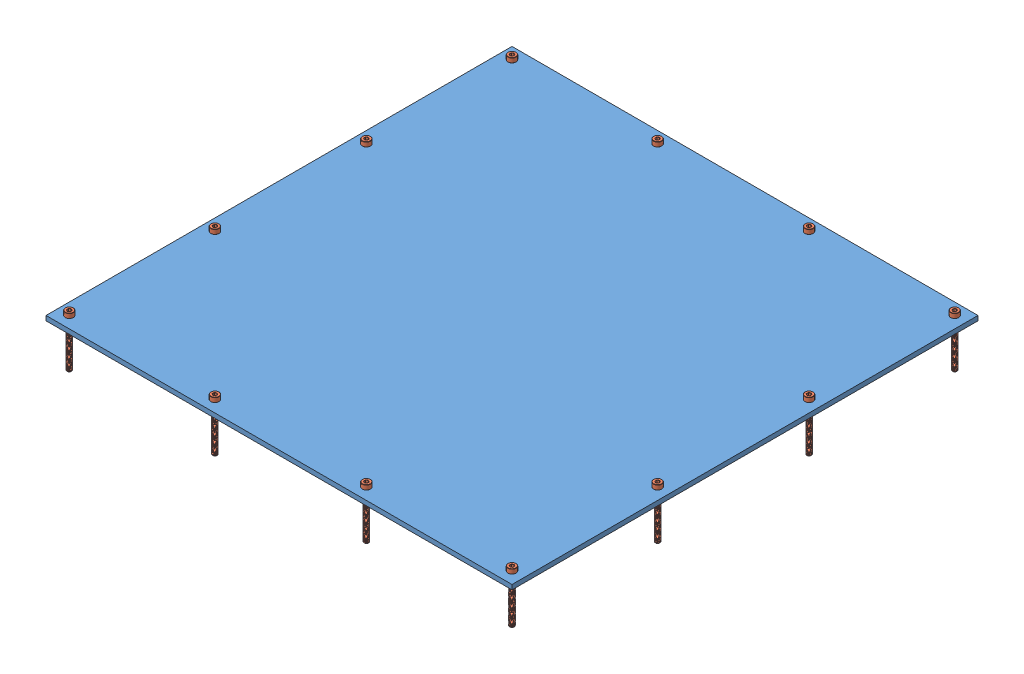
SolidWorks assembly Assem1, configuration Default. Lengths in mm.
Overall size (400 45 400).
13 component instances, 2 part files, 2 mates.
Components (placement in the parent):
- AluminumPlate-1: AluminumPlate [Default] at (130.93 169.5501 342.0003) size (400 4 400)
- M4_41MM-1: M4_41MM [По умолчанию] at (-59.07 173.5501 532.0003) x (0.999999 0 0.001128) z (-0.001128 0 0.999999) size (7 45 7)
- M4_41MM-2: M4_41MM [По умолчанию] at (-59.07 173.5501 407.0003) x (0.999999 0 0.001128) z (-0.001128 0 0.999999) size (7 45 7)
- M4_41MM-3: M4_41MM [По умолчанию] at (65.93 173.5501 532.0003) x (0.999999 0 0.001128) z (-0.001128 0 0.999999) size (7 45 7)
- M4_41MM-5: M4_41MM [По умолчанию] at (-59.07 173.5501 277.0003) x (0.999999 0 -0.001128) z (0.001128 0 0.999999) size (7 45 7)
- M4_41MM-6: M4_41MM [По умолчанию] at (-59.07 173.5501 152.0003) x (0.999999 0 -0.001128) z (0.001128 0 0.999999) size (7 45 7)
- M4_41MM-7: M4_41MM [По умолчанию] at (65.93 173.5501 152.0003) x (0.999999 0 -0.001128) z (0.001128 0 0.999999) size (7 45 7)
- M4_41MM-8: M4_41MM [По умолчанию] at (195.93 173.5501 152.0003) x (-0.999999 0 -0.001128) z (0.001128 0 -0.999999) size (7 45 7)
- M4_41MM-9: M4_41MM [По умолчанию] at (320.93 173.5501 152.0003) x (-0.999999 0 -0.001128) z (0.001128 0 -0.999999) size (7 45 7)
- M4_41MM-10: M4_41MM [По умолчанию] at (320.93 173.5501 277.0003) x (-0.999999 0 -0.001128) z (0.001128 0 -0.999999) size (7 45 7)
- M4_41MM-11: M4_41MM [По умолчанию] at (320.93 173.5501 532.0003) x (-0.999999 0 0.001128) z (-0.001128 0 -0.999999) size (7 45 7)
- M4_41MM-12: M4_41MM [По умолчанию] at (195.93 173.5501 532.0003) x (-0.999999 0 0.001128) z (-0.001128 0 -0.999999) size (7 45 7)
- M4_41MM-13: M4_41MM [По умолчанию] at (320.93 173.5501 407.0003) x (-0.999999 0 0.001128) z (-0.001128 0 -0.999999) size (7 45 7)
Mates (geometry in assembly coordinates):
- Concentric1: concentric aligned: cylinder of AluminumPlate-1 through (-59.07 173.5501 532.0003) axis (0 -1 0) radius 2; cylinder of M4_41MM-1 through (-59.07 177.5501 532.0003) axis (0 -1 0) radius 3.5
- Coincident1: coincident anti-aligned: plane of AluminumPlate-1 through (130.93 173.5501 342.0003) normal (0 1 0); plane of M4_41MM-1 through (-59.07 173.5501 532.0003) normal (0 -1 0)
